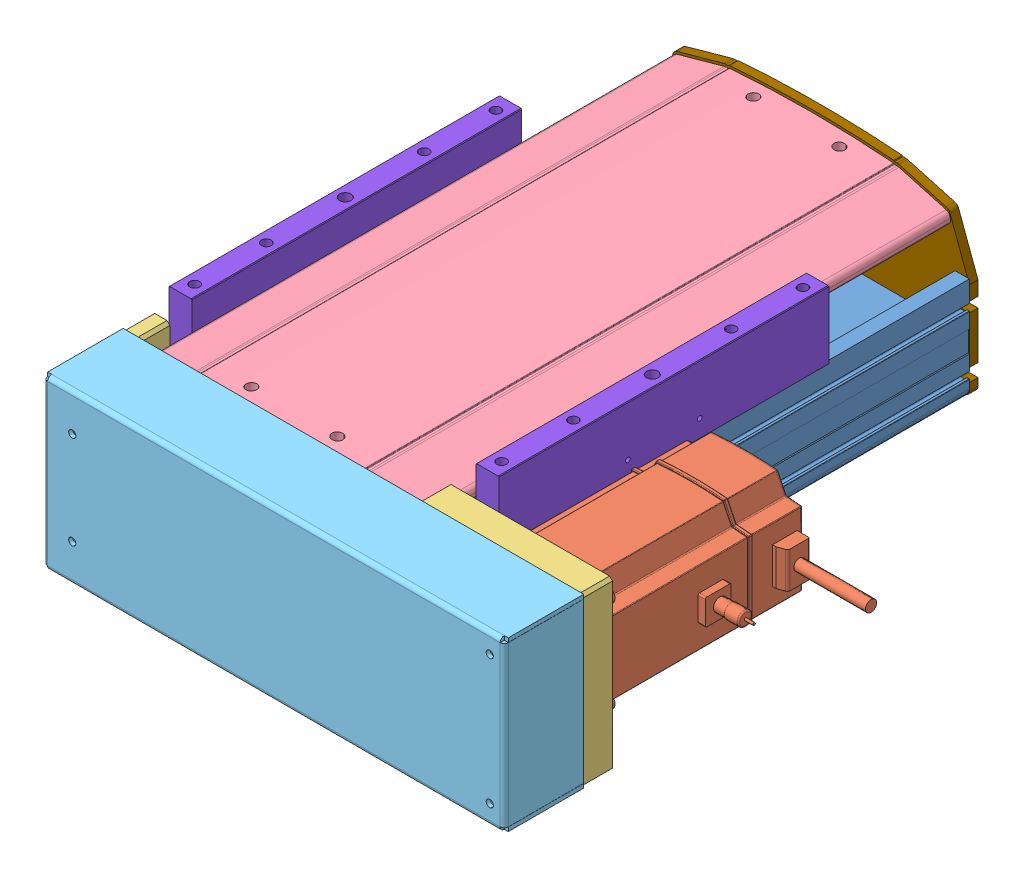
SolidWorks assembly S22-BL-750W, configuration 默认. Lengths in mm.
Overall size (384.91 122 432.01).
11 component instances, 9 part files, 36 mates.
Components (placement in the parent):
- S22-BL底座^S22-BL-750W-1: S22-BL底座^S22-BL-750W [默认] at origin size (220 72.2 350.5) (virtual)
- 750W电机^S22-BL-750W-1: 750W电机^S22-BL-750W [默认] at (162.71 60.5 33.25) x (0 1 0) z (0 0 1) size (82 139.7 182) (virtual)
- S22-BL-P75电机板^S22-BL-750W-1: S22-BL-P75电机板^S22-BL-750W [默认] at (0.21 0 175.25) size (321 117 20) (virtual)
- S22-BL上盖^S22-BL-750W-1: S22-BL上盖^S22-BL-750W [默认] at (0 117.9988 10) size (193.4 19.6 370.5) (virtual)
- S22-BL盖子^S22-BL-750W-1: S22-BL盖子^S22-BL-750W [默认] at (51.21 59.5 250.75) size (321.02 117 55.51) (virtual)
- EE-SX672 传感器^S22-BL-750W-1: EE-SX672 传感器^S22-BL-750W [默认] at (-116.75 60.1 -14.25) x (-1 0 0) z (0 0 1) size (13.5 27.4 26.1) (virtual)
- S22-GY外置感应片^S22-BL-750W-1: S22-GY外置感应片^S22-BL-750W [默认] at (-115.8 87 42.75) x (0 0 -1) z (1 0 0) size (70 27 0.8) (virtual)
- EE-SX672 传感器^S22-BL-750W-2: EE-SX672 传感器^S22-BL-750W [默认] at (-116.75 60.1 52.65) x (-1 0 0) z (0 0 1) size (13.5 27.4 26.1) (virtual)
- EE-SX672 传感器^S22-BL-750W-3: EE-SX672 传感器^S22-BL-750W [默认] at (-116.75 60.1 26.55) x (-1 0 0) z (0 0 1) size (13.5 27.4 26.1) (virtual)
- S22-BL-SFS25滑座^S22-BL-750W-1: S22-BL-SFS25滑座^S22-BL-750W [默认] at (0 0 42.75) size (230 80 230) (virtual)
- 复件 端盖S22-T22M^S22-BL-750W-1: 复件 端盖S22-T22M^S22-BL-750W [默认] at (0 1.2 -181.25) size (220 118.5 6) (virtual)
Mates (geometry in assembly coordinates):
- 重合1: coincident: plane of S22-BL底座^S22-BL-750W-1 through (0 0 0) normal (1 0 0); plane of assembly through (0 0 0) normal (1 0 0)
- 重合2: coincident: plane of S22-BL底座^S22-BL-750W-1 through (0 0 0) normal (0 1 0); plane of assembly through (0 0 0) normal (0 1 0)
- 重合3: coincident: plane of S22-BL底座^S22-BL-750W-1 through (0 0 0) normal (0 0 1); plane of assembly through (0 0 0) normal (0 0 1)
- 重合28: coincident: plane of S22-BL底座^S22-BL-750W-1 through (0 0 0) normal (0 1 0); plane of S22-BL-P75电机板^S22-BL-750W-1 through (0.21 0 175.25) normal (0 1 0)
- 重合29: coincident: plane of S22-BL底座^S22-BL-750W-1 through (0 0 0) normal (1 0 0); plane of S22-BL-P75电机板^S22-BL-750W-1 through (0.21 0 400.25) normal (1 0 0)
- 重合30: coincident: plane of S22-BL底座^S22-BL-750W-1 through (-104.5 14 175.25) normal (0 0 1); plane of S22-BL-P75电机板^S22-BL-750W-1 through (0.21 0 175.25) normal (0 0 -1)
- 重合36: coincident: plane of S22-BL底座^S22-BL-750W-1 through (0 0 0) normal (1 0 0); plane of S22-BL上盖^S22-BL-750W-1 through (0 117.9988 10) normal (1 0 0)
- 重合130: coincident: plane of S22-BL-P75电机板^S22-BL-750W-1 through (211.71 118 195.25) normal (0 1 0); plane of S22-BL盖子^S22-BL-750W-1 through (208.91 118 247.95) normal (0 1 0)
- 重合131: coincident: plane of S22-BL-P75电机板^S22-BL-750W-1 through (-109.29 18.5 195.25) normal (-1 0 0); plane of S22-BL盖子^S22-BL-750W-1 through (-109.29 115.1 247.95) normal (-1 0 0)
- 重合132: coincident: plane of S22-BL-P75电机板^S22-BL-750W-1 through (0.21 0 195.25) normal (0 0 1); plane of S22-BL盖子^S22-BL-750W-1 through (208.91 118 195.25) normal (0 0 -1)
- 重合151: coincident: plane of S22-BL-P75电机板^S22-BL-750W-1 through (0.21 0 195.25) normal (0 0 1); plane of S22-BL上盖^S22-BL-750W-1 through (59.5897 110.29 195.25) normal (0 0 1)
- Distance1: distance = 9 mm: plane of 750W电机^S22-BL-750W-1 through (202.71 93.5 167.25) normal (1 0 0); plane of S22-BL-P75电机板^S22-BL-750W-1 through (211.71 1 195.25) normal (1 0 0)
- Distance2: distance = 18 mm: plane of 750W电机^S22-BL-750W-1 through (129.71 100.5 392.25) normal (0 1 0); plane of S22-BL-P75电机板^S22-BL-750W-1 through (211.71 118 420.25) normal (0 1 0)
- Coincident3: coincident: plane of 750W电机^S22-BL-750W-1 through (162.71 60.5 175.25) normal (0 0 1); plane of S22-BL-P75电机板^S22-BL-750W-1 through (0.21 0 175.25) normal (0 0 -1)
- Distance3: distance = 122 mm: plane of S22-BL-SFS25滑座^S22-BL-750W-1 through (99 122 157.75) normal (0 1 0); plane of S22-BL底座^S22-BL-750W-1 through (110 0 175.25) normal (0 -1 0)
- Coincident5: coincident: plane of S22-BL底座^S22-BL-750W-1 through (0 0 0) normal (1 0 0); plane of S22-BL-SFS25滑座^S22-BL-750W-1 through (0 0 42.75) normal (1 0 0)
- Distance4: distance = 117.9988 mm: plane of S22-BL上盖^S22-BL-750W-1 through (0 117.9988 10) normal (0 1 0); plane of S22-BL底座^S22-BL-750W-1 through (0 0 0) normal (0 1 0)
- Coincident6: coincident: plane of EE-SX672 传感器^S22-BL-750W-2 through (-110 71.2 58.95) normal (1 0 0); plane of EE-SX672 传感器^S22-BL-750W-3 through (-110 71.2 32.85) normal (1 0 0)
- Coincident7: coincident: plane of EE-SX672 传感器^S22-BL-750W-1 through (-110 71.2 -7.95) normal (1 0 0); plane of EE-SX672 传感器^S22-BL-750W-2 through (-110 71.2 58.95) normal (1 0 0)
- Coincident8: coincident: plane of EE-SX672 传感器^S22-BL-750W-2 through (-110 49 58.95) normal (0 -1 0); plane of EE-SX672 传感器^S22-BL-750W-3 through (-110 49 32.85) normal (0 -1 0)
- Coincident9: coincident: plane of EE-SX672 传感器^S22-BL-750W-1 through (-110 49 -7.95) normal (0 -1 0); plane of EE-SX672 传感器^S22-BL-750W-2 through (-110 49 58.95) normal (0 -1 0)
- Coincident10: coincident: plane of EE-SX672 传感器^S22-BL-750W-2 through (-113 52.2 42.75) normal (0 0 -1); plane of EE-SX672 传感器^S22-BL-750W-3 through (-113 52.2 42.75) normal (0 0 1)
- Coincident11: coincident: plane of S22-BL底座^S22-BL-750W-1 through (-110 42 175.25) normal (-1 0 0); plane of EE-SX672 传感器^S22-BL-750W-2 through (-110 71.2 58.95) normal (1 0 0)
- Distance5: distance = 49 mm: plane of EE-SX672 传感器^S22-BL-750W-1 through (-110 49 -7.95) normal (0 -1 0); plane of S22-BL底座^S22-BL-750W-1 through (-110 0 175.25) normal (0 -1 0)
- Coincident13: coincident: plane of S22-BL-SFS25滑座^S22-BL-750W-1 through (-115 122 157.75) normal (-1 0 0); plane of S22-GY外置感应片^S22-BL-750W-1 through (-115 91 76.75) normal (1 0 0)
- Concentric1: concentric: cylinder of S22-BL-SFS25滑座^S22-BL-750W-1 through (-115 87 67.75) axis (-1 0 0) radius 1.65; cylinder of S22-GY外置感应片^S22-BL-750W-1 through (-115 87 67.75) axis (-1 0 0) radius 2.75
- Concentric2: concentric: cylinder of S22-BL-SFS25滑座^S22-BL-750W-1 through (-115 87 17.75) axis (-1 0 0) radius 1.65; cylinder of S22-GY外置感应片^S22-BL-750W-1 through (-115 87 17.75) axis (-1 0 0) radius 2.75
- 距离1: distance = 189 mm: plane of EE-SX672 传感器^S22-BL-750W-2 through (-123.5 49 58.95) normal (0 0 1); plane of S22-BL盖子^S22-BL-750W-1 through (208.91 118 250.75) normal (0 0 1)
- 宽度1: width: plane of EE-SX672 传感器^S22-BL-750W-3 through (-123.5 49 32.85) normal (0 0 1); plane of EE-SX672 传感器^S22-BL-750W-2 through (-123.5 49 52.65) normal (0 0 -1); plane of S22-GY外置感应片^S22-BL-750W-1 through (-115 65 36.75) normal (0 0 -1); plane of S22-GY外置感应片^S22-BL-750W-1 through (-115 65 48.75) normal (0 0 1)
- 距离3: distance = 1.2 mm: plane of S22-BL底座^S22-BL-750W-1 through (110 0 175.25) normal (0 -1 0); plane of 复件 端盖S22-T22M^S22-BL-750W-1 through (-110 1.2 -175.25) normal (0 -1 0)
- 宽度2: width: plane of 复件 端盖S22-T22M^S22-BL-750W-1 through (110 18.7 -175.25) normal (1 0 0); plane of 复件 端盖S22-T22M^S22-BL-750W-1 through (-110 18.7 -175.25) normal (-1 0 0); plane of S22-BL底座^S22-BL-750W-1 through (-109.5 27.5 175.25) normal (-1 0 0); plane of S22-BL底座^S22-BL-750W-1 through (109.5 27.5 175.25) normal (1 0 0)
- 重合156: coincident: plane of S22-BL底座^S22-BL-750W-1 through (-104.5 14 -175.25) normal (0 0 -1); plane of 复件 端盖S22-T22M^S22-BL-750W-1 through (92.7005 103.8004 -175.25) normal (0 0 1)
- 距离4: distance = 161 mm: plane of EE-SX672 传感器^S22-BL-750W-1 through (-123.5 49 -14.25) normal (0 0 -1); plane of S22-BL底座^S22-BL-750W-1 through (-104.5 14 -175.25) normal (0 0 -1)
- 距离5: distance = 52.71 mm: cylinder of 750W电机^S22-BL-750W-1 through (162.71 60.5 178.25) axis (0 0 1) radius 9.5; plane of S22-BL底座^S22-BL-750W-1 through (110 16.25 175.25) normal (1 0 0)
- 距离6: distance = 60.5 mm: plane of S22-BL底座^S22-BL-750W-1 through (110 0 175.25) normal (0 -1 0); cylinder of 750W电机^S22-BL-750W-1 through (162.71 60.5 178.25) axis (0 0 1) radius 9.5
- 距离7: distance = 208 mm: cylinder of S22-BL-SFS25滑座^S22-BL-750W-1 through (-107 122 42.75) axis (0 1 0) radius 4; plane of S22-BL盖子^S22-BL-750W-1 through (208.91 118 250.75) normal (0 0 1)
